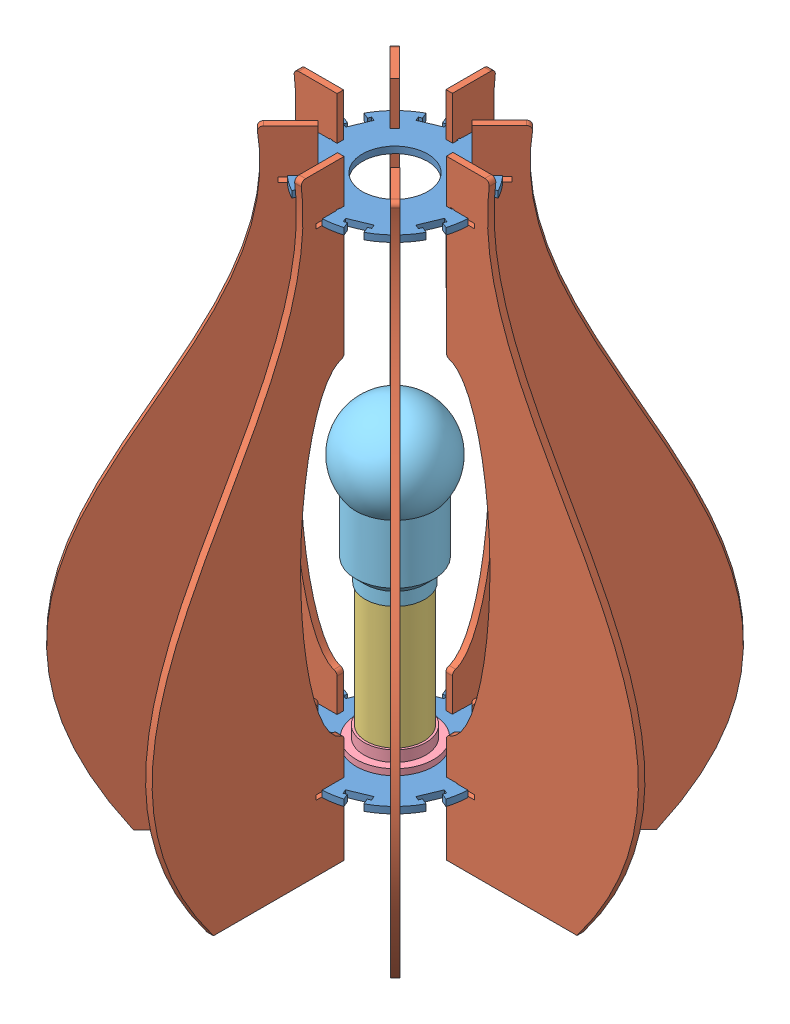
SolidWorks assembly final assembly, configuration Default. Lengths in mm.
Overall size (255.7 280 255.7).
13 component instances, 5 part files, 12 mates.
Components (placement in the parent):
- final disk-1: final disk [Default] at (-62.0679 9.1344 25.5275) size (69.95 3 69.95)
- final slide-1: final slide [Default] at (-37.0857 -187.286 23.9124) size (102.87 280 3)
- final slide-2: final slide [Default] at (-45.5449 -187.286 6.7204) x (0.707107 0 -0.707107) z (0.707107 0 0.707107) size (102.87 280 3)
- final slide-3: final slide [Default] at (-63.683 -187.286 0.5454) x (0 0 -1) z (1 0 0) size (102.87 280 3)
- final slide-4: final slide [Default] at (-80.875 -187.286 9.0046) x (-0.707107 0 -0.707107) z (0.707107 0 -0.707107) size (102.87 280 3)
- final slide-5: final slide [Default] at (-87.05 -187.286 27.1427) x (-1 0 0) z (0 0 -1) size (102.87 280 3)
- final slide-6: final slide [Default] at (-78.5909 -187.286 44.3347) x (-0.707107 0 0.707107) z (-0.707107 0 -0.707107) size (102.87 280 3)
- final slide-7: final slide [Default] at (-60.4527 -187.286 50.5097) x (0 0 1) z (-1 0 0) size (102.87 280 3)
- final slide-8: final slide [Default] at (-43.2608 -187.286 42.0505) x (0.707107 0 0.707107) z (-0.707107 0 0.707107) size (102.87 280 3)
- final disk-2: final disk [Default] at (-61.9638 -215.0756 25.64) x (0 0 1) z (1 0 0) size (69.95 3 69.95)
- light fitting part 1-1: light fitting part 1 [Default] at (-61.9638 -221.0756 25.64) size (35.5 70.5 35.5)
- light fitting part 2-1: light fitting part 2 [Default] at (-61.9638 -215.0756 25.64) size (35.5 7.8 35.5)
- light bulb-2: light bulb [Default] at (-61.9638 -176.12 25.64) size (45 98.79 45)
Mates (geometry in assembly coordinates):
- Coincident1: coincident anti-aligned: plane of final disk-1 through (-62.0679 12.1344 26.9124) normal (0 0 -1); plane of final slide-1 through (29.7461 -102.4845 26.9124) normal (0 0 1)
- Coincident2: coincident anti-aligned: plane of final disk-1 through (-62.0679 9.1344 25.5275) normal (0 -1 0); plane of final slide-1 through (-37.0857 9.1344 26.9124) normal (0 1 0)
- Coincident4: coincident anti-aligned: plane of final disk-1 through (-37.0857 11.6344 27.0418) normal (1 0 0); plane of final slide-1 through (-37.0857 11.9244 26.9124) normal (-1 0 0)
- Coincident5: coincident anti-aligned: plane of final slide-6 through (-80.7122 -217.5756 42.2133) normal (0 1 0); plane of final disk-2 through (-61.9638 -217.5756 25.64) normal (0 -1 0)
- Coincident6: coincident anti-aligned: plane of final slide-6 through (-125.8481 -102.4845 91.5919) normal (0.707107 0 0.707107); plane of final disk-2 through (-60.93 -218.0756 26.6738) normal (-0.707107 0 -0.707107)
- Coincident7: coincident anti-aligned: plane of final slide-6 through (-80.7122 -217.5756 42.2133) normal (0.707107 0 -0.707107); plane of final disk-2 through (-78.5497 -217.5756 44.3758) normal (-0.707107 0 0.707107)
- Concentric1: concentric anti-aligned: cylinder of final disk-2 through (-61.9638 -218.0756 25.64) axis (0 1 0) radius 15; cylinder of light fitting part 1-1 through (-61.9638 -150.5756 25.64) axis (0 -1 0) radius 13.2
- Coincident8: coincident anti-aligned: plane of final disk-2 through (-61.9638 -218.0756 25.64) normal (0 -1 0); plane of light fitting part 1-1 through (-61.9638 -218.0756 25.64) normal (0 1 0)
- Concentric2: concentric aligned: cylinder of light fitting part 1-1 through (-61.9638 -150.5756 25.64) axis (0 -1 0) radius 13.2; cylinder of light fitting part 2-1 through (-61.9638 -198.0756 25.64) axis (0 -1 0) radius 13.2
- Coincident9: coincident anti-aligned: plane of final disk-2 through (-61.9638 -215.0756 25.64) normal (0 1 0); plane of light fitting part 2-1 through (-61.9638 -215.0756 25.64) normal (0 -1 0)
- Concentric3: concentric: cylinder of light fitting part 1-1 through (-61.9638 -196.5756 25.64) axis (0 1 0) radius 12; cylinder of light bulb-2 through (-61.9638 -70.4068 25.64) axis (0 1 0) radius 13.76
- Coincident10: coincident anti-aligned: plane of light fitting part 1-1 through (-61.9638 -150.5756 25.64) normal (0 1 0); plane of light bulb-2 through (-48.2038 -150.5756 25.64) normal (0 -1 0)
